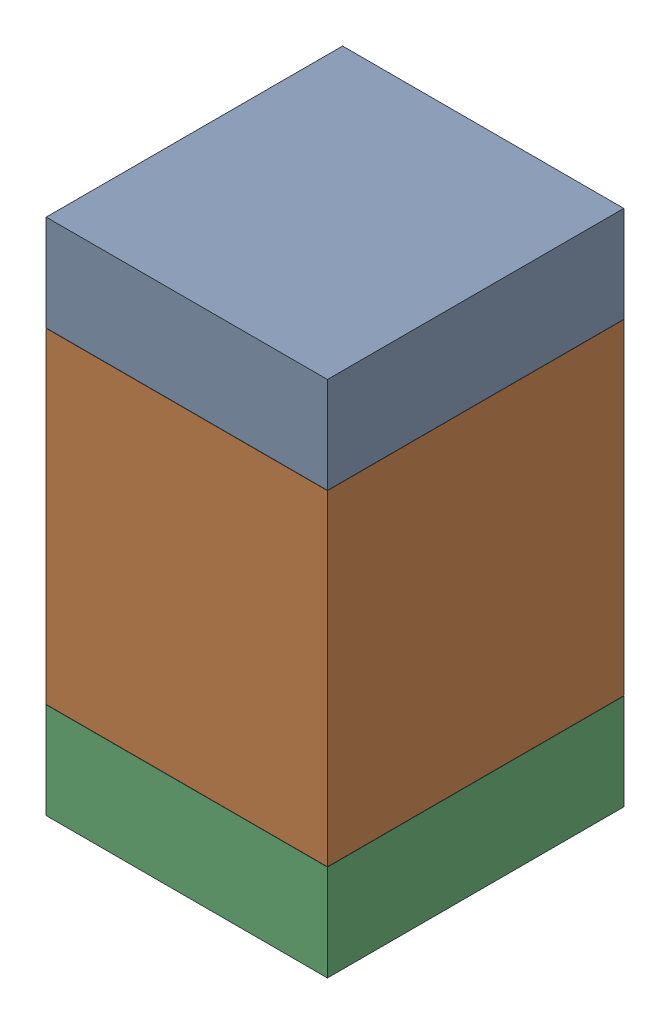
SolidWorks assembly R5, configuration Default. Lengths in mm.
Overall size (0.95 1.75 1).
6 component instances, 2 part files, 0 mates.
Components (placement in the parent):
- 6575495072-1: 6575495072 [Default] at (16.637 19.6355 0) size (0.95 0.32 1)
  - Extruded_6-1: Extruded_6 [Default] at origin size (0.95 0.32 1)
- 6575494912-1: 6575494912 [Default] at (16.637 18.923 0) size (0.95 1.1 1)
  - Extruded_7-1: Extruded_7 [Default] at origin size (0.95 1.1 1)
- 6575495072-2: 6575495072 [Default] at (16.637 18.2105 0) size (0.95 0.32 1)
  - Extruded_6-1: Extruded_6 [Default] at origin size (0.95 0.32 1)
